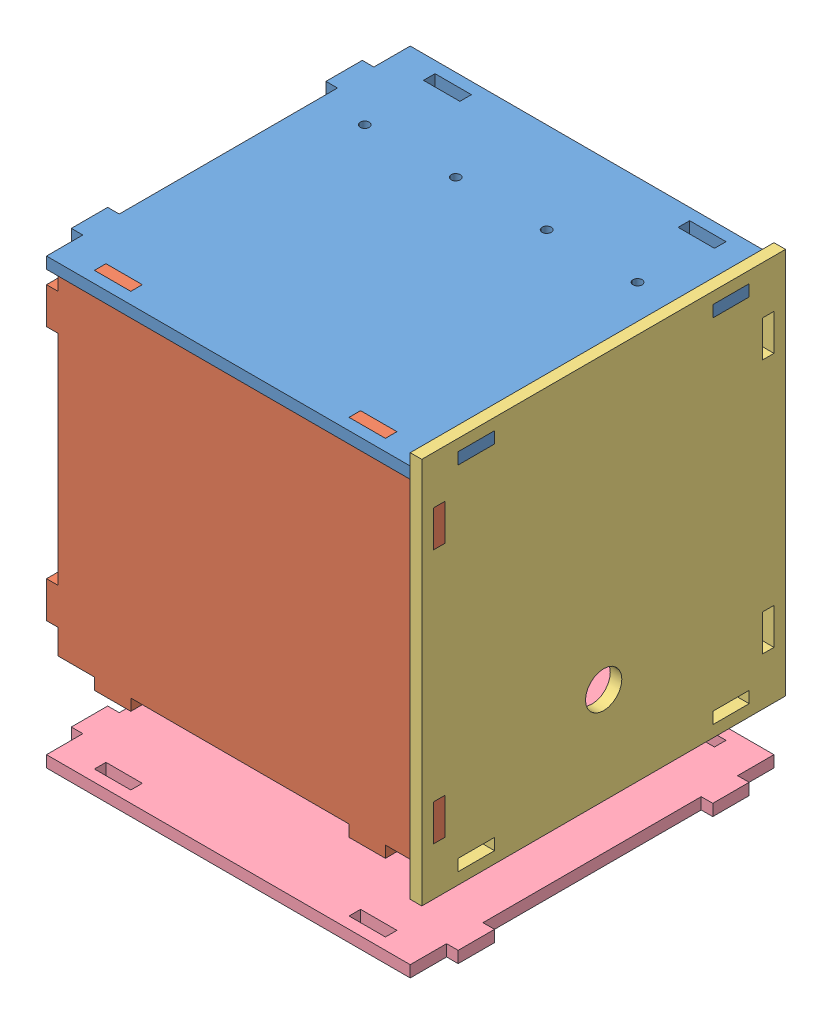
SolidWorks assembly assembly final, configuration Default. Lengths in mm.
Overall size (127.62 125.08 118.59).
4 component instances, 4 part files, 6 mates.
Components (placement in the parent):
- top-1: top [Default] at (-5.9046 57.1468 127.1142) size (127.62 3.17 118.59)
- frontback-1: frontback [Default] at (-5.9046 -39.6782 120.7642) size (106.35 100 3.17)
- side plate - power-1: side plate - power [Default] at (94.0954 -42.8532 127.1142) size (3.17 106.35 100)
- bottom-1: bottom [Default] at (-17.3612 -61.5802 54.1869) size (106.35 3.17 100)
Mates (geometry in assembly coordinates):
- Coincident2: coincident aligned: line of top-1 through (14.0954 60.3218 123.9392) axis (0 0 -1); line of frontback-1 through (14.0954 60.3218 123.9392) axis (0 0 -1)
- Coincident4: coincident aligned: line of top-1 through (14.0954 60.3218 120.7642) axis (-1 0 0); line of frontback-1 through (14.0954 60.3218 120.7642) axis (-1 0 0)
- Coincident5: coincident aligned: line of top-1 through (97.2704 60.3218 117.1142) axis (0 -1 0); line of side plate - power-1 through (97.2704 60.3218 117.1142) axis (0 -1 0)
- Coincident6: coincident aligned: line of top-1 through (97.2704 57.1468 117.1142) axis (0 0 -1); line of side plate - power-1 through (97.2704 57.1468 117.1142) axis (0 0 -1)
- Coincident7: coincident: plane of frontback-1 through (4.0954 -36.5032 123.9392) normal (-1 0 0); line of bottom-1 through (4.0954 -58.4052 120.7642) axis (0 0 1)
- Coincident8: coincident anti-aligned: plane of frontback-1 through (-5.9046 -39.6782 123.9392) normal (0 0 1); plane of bottom-1 through (4.0954 -58.4052 123.9392) normal (0 0 -1)
